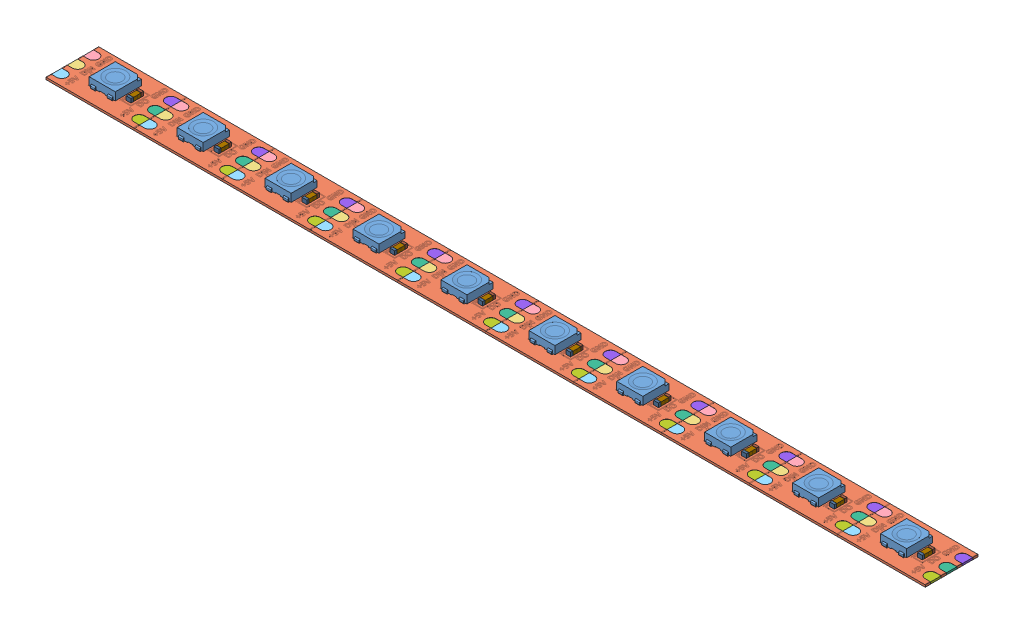
SolidWorks assembly LED_strip, configuration Défaut. Lengths in mm.
Overall size (166.7 2.05 10).
120 component instances, 11 part files, 0 mates.
Components (placement in the parent):
- WS2812B Black 60leds_m v7.step-1: WS2812B Black 60leds_m v7.step [Défaut] at (-9.957 -1.0414 11.6695) size (16.67 2.05 10)
  - WS2812_RGB_LED_updated v3.step-1: WS2812_RGB_LED_updated v3.step [Défaut] at (8.1333 0.55 5) x (1 0 0) z (0 1 0) size (4.95 5.35 1.7)
  - WS2812B Black 60leds_m.step-1: WS2812B Black 60leds_m.step [Défaut] at origin size (16.67 0.41 10)
  - WS2812B Black 60leds_m-0.step-1: WS2812B Black 60leds_m-0.step [Défaut] at origin size (2 0.36 2)
  - WS2812B Black 60leds_m-1.step-1: WS2812B Black 60leds_m-1.step [Défaut] at origin size (2 0.36 2)
  - WS2812B Black 60leds_m-2.step-1: WS2812B Black 60leds_m-2.step [Défaut] at origin size (2 0.36 2)
  - WS2812B Black 60leds_m-3.step-1: WS2812B Black 60leds_m-3.step [Défaut] at origin size (2 0.36 2)
  - WS2812B Black 60leds_m-4.step-1: WS2812B Black 60leds_m-4.step [Défaut] at origin size (2 0.36 2)
  - WS2812B Black 60leds_m-5.step-1: WS2812B Black 60leds_m-5.step [Défaut] at origin size (2 0.36 2)
  - WS2812B Black 60leds_m-6.step-1: WS2812B Black 60leds_m-6.step [Défaut] at origin size (0.9 0.7 1.5)
  - WS2812B Black 60leds_m-7.step-1: WS2812B Black 60leds_m-7.step [Défaut] at origin size (0.9 0.75 0.45)
  - WS2812B Black 60leds_m-8.step-1: WS2812B Black 60leds_m-8.step [Défaut] at origin size (0.9 0.75 0.45)
- WS2812B Black 60leds_m v7.step-2: WS2812B Black 60leds_m v7.step [Défaut] at (6.713 -1.0414 11.6695) size (16.67 2.05 10)
  - WS2812_RGB_LED_updated v3.step-1: WS2812_RGB_LED_updated v3.step [Défaut] at (8.1333 0.55 5) x (1 0 0) z (0 1 0) size (4.95 5.35 1.7)
  - WS2812B Black 60leds_m.step-1: WS2812B Black 60leds_m.step [Défaut] at origin size (16.67 0.41 10)
  - WS2812B Black 60leds_m-0.step-1: WS2812B Black 60leds_m-0.step [Défaut] at origin size (2 0.36 2)
  - WS2812B Black 60leds_m-1.step-1: WS2812B Black 60leds_m-1.step [Défaut] at origin size (2 0.36 2)
  - WS2812B Black 60leds_m-2.step-1: WS2812B Black 60leds_m-2.step [Défaut] at origin size (2 0.36 2)
  - WS2812B Black 60leds_m-3.step-1: WS2812B Black 60leds_m-3.step [Défaut] at origin size (2 0.36 2)
  - WS2812B Black 60leds_m-4.step-1: WS2812B Black 60leds_m-4.step [Défaut] at origin size (2 0.36 2)
  - WS2812B Black 60leds_m-5.step-1: WS2812B Black 60leds_m-5.step [Défaut] at origin size (2 0.36 2)
  - WS2812B Black 60leds_m-6.step-1: WS2812B Black 60leds_m-6.step [Défaut] at origin size (0.9 0.7 1.5)
  - WS2812B Black 60leds_m-7.step-1: WS2812B Black 60leds_m-7.step [Défaut] at origin size (0.9 0.75 0.45)
  - WS2812B Black 60leds_m-8.step-1: WS2812B Black 60leds_m-8.step [Défaut] at origin size (0.9 0.75 0.45)
- WS2812B Black 60leds_m v7.step-3: WS2812B Black 60leds_m v7.step [Défaut] at (23.383 -1.0414 11.6695) size (16.67 2.05 10)
  - WS2812_RGB_LED_updated v3.step-1: WS2812_RGB_LED_updated v3.step [Défaut] at (8.1333 0.55 5) x (1 0 0) z (0 1 0) size (4.95 5.35 1.7)
  - WS2812B Black 60leds_m.step-1: WS2812B Black 60leds_m.step [Défaut] at origin size (16.67 0.41 10)
  - WS2812B Black 60leds_m-0.step-1: WS2812B Black 60leds_m-0.step [Défaut] at origin size (2 0.36 2)
  - WS2812B Black 60leds_m-1.step-1: WS2812B Black 60leds_m-1.step [Défaut] at origin size (2 0.36 2)
  - WS2812B Black 60leds_m-2.step-1: WS2812B Black 60leds_m-2.step [Défaut] at origin size (2 0.36 2)
  - WS2812B Black 60leds_m-3.step-1: WS2812B Black 60leds_m-3.step [Défaut] at origin size (2 0.36 2)
  - WS2812B Black 60leds_m-4.step-1: WS2812B Black 60leds_m-4.step [Défaut] at origin size (2 0.36 2)
  - WS2812B Black 60leds_m-5.step-1: WS2812B Black 60leds_m-5.step [Défaut] at origin size (2 0.36 2)
  - WS2812B Black 60leds_m-6.step-1: WS2812B Black 60leds_m-6.step [Défaut] at origin size (0.9 0.7 1.5)
  - WS2812B Black 60leds_m-7.step-1: WS2812B Black 60leds_m-7.step [Défaut] at origin size (0.9 0.75 0.45)
  - WS2812B Black 60leds_m-8.step-1: WS2812B Black 60leds_m-8.step [Défaut] at origin size (0.9 0.75 0.45)
- WS2812B Black 60leds_m v7.step-4: WS2812B Black 60leds_m v7.step [Défaut] at (40.053 -1.0414 11.6695) size (16.67 2.05 10)
  - WS2812_RGB_LED_updated v3.step-1: WS2812_RGB_LED_updated v3.step [Défaut] at (8.1333 0.55 5) x (1 0 0) z (0 1 0) size (4.95 5.35 1.7)
  - WS2812B Black 60leds_m.step-1: WS2812B Black 60leds_m.step [Défaut] at origin size (16.67 0.41 10)
  - WS2812B Black 60leds_m-0.step-1: WS2812B Black 60leds_m-0.step [Défaut] at origin size (2 0.36 2)
  - WS2812B Black 60leds_m-1.step-1: WS2812B Black 60leds_m-1.step [Défaut] at origin size (2 0.36 2)
  - WS2812B Black 60leds_m-2.step-1: WS2812B Black 60leds_m-2.step [Défaut] at origin size (2 0.36 2)
  - WS2812B Black 60leds_m-3.step-1: WS2812B Black 60leds_m-3.step [Défaut] at origin size (2 0.36 2)
  - WS2812B Black 60leds_m-4.step-1: WS2812B Black 60leds_m-4.step [Défaut] at origin size (2 0.36 2)
  - WS2812B Black 60leds_m-5.step-1: WS2812B Black 60leds_m-5.step [Défaut] at origin size (2 0.36 2)
  - WS2812B Black 60leds_m-6.step-1: WS2812B Black 60leds_m-6.step [Défaut] at origin size (0.9 0.7 1.5)
  - WS2812B Black 60leds_m-7.step-1: WS2812B Black 60leds_m-7.step [Défaut] at origin size (0.9 0.75 0.45)
  - WS2812B Black 60leds_m-8.step-1: WS2812B Black 60leds_m-8.step [Défaut] at origin size (0.9 0.75 0.45)
- WS2812B Black 60leds_m v7.step-5: WS2812B Black 60leds_m v7.step [Défaut] at (56.723 -1.0414 11.6695) size (16.67 2.05 10)
  - WS2812_RGB_LED_updated v3.step-1: WS2812_RGB_LED_updated v3.step [Défaut] at (8.1333 0.55 5) x (1 0 0) z (0 1 0) size (4.95 5.35 1.7)
  - WS2812B Black 60leds_m.step-1: WS2812B Black 60leds_m.step [Défaut] at origin size (16.67 0.41 10)
  - WS2812B Black 60leds_m-0.step-1: WS2812B Black 60leds_m-0.step [Défaut] at origin size (2 0.36 2)
  - WS2812B Black 60leds_m-1.step-1: WS2812B Black 60leds_m-1.step [Défaut] at origin size (2 0.36 2)
  - WS2812B Black 60leds_m-2.step-1: WS2812B Black 60leds_m-2.step [Défaut] at origin size (2 0.36 2)
  - WS2812B Black 60leds_m-3.step-1: WS2812B Black 60leds_m-3.step [Défaut] at origin size (2 0.36 2)
  - WS2812B Black 60leds_m-4.step-1: WS2812B Black 60leds_m-4.step [Défaut] at origin size (2 0.36 2)
  - WS2812B Black 60leds_m-5.step-1: WS2812B Black 60leds_m-5.step [Défaut] at origin size (2 0.36 2)
  - WS2812B Black 60leds_m-6.step-1: WS2812B Black 60leds_m-6.step [Défaut] at origin size (0.9 0.7 1.5)
  - WS2812B Black 60leds_m-7.step-1: WS2812B Black 60leds_m-7.step [Défaut] at origin size (0.9 0.75 0.45)
  - WS2812B Black 60leds_m-8.step-1: WS2812B Black 60leds_m-8.step [Défaut] at origin size (0.9 0.75 0.45)
- WS2812B Black 60leds_m v7.step-6: WS2812B Black 60leds_m v7.step [Défaut] at (73.393 -1.0414 11.6695) size (16.67 2.05 10)
  - WS2812_RGB_LED_updated v3.step-1: WS2812_RGB_LED_updated v3.step [Défaut] at (8.1333 0.55 5) x (1 0 0) z (0 1 0) size (4.95 5.35 1.7)
  - WS2812B Black 60leds_m.step-1: WS2812B Black 60leds_m.step [Défaut] at origin size (16.67 0.41 10)
  - WS2812B Black 60leds_m-0.step-1: WS2812B Black 60leds_m-0.step [Défaut] at origin size (2 0.36 2)
  - WS2812B Black 60leds_m-1.step-1: WS2812B Black 60leds_m-1.step [Défaut] at origin size (2 0.36 2)
  - WS2812B Black 60leds_m-2.step-1: WS2812B Black 60leds_m-2.step [Défaut] at origin size (2 0.36 2)
  - WS2812B Black 60leds_m-3.step-1: WS2812B Black 60leds_m-3.step [Défaut] at origin size (2 0.36 2)
  - WS2812B Black 60leds_m-4.step-1: WS2812B Black 60leds_m-4.step [Défaut] at origin size (2 0.36 2)
  - WS2812B Black 60leds_m-5.step-1: WS2812B Black 60leds_m-5.step [Défaut] at origin size (2 0.36 2)
  - WS2812B Black 60leds_m-6.step-1: WS2812B Black 60leds_m-6.step [Défaut] at origin size (0.9 0.7 1.5)
  - WS2812B Black 60leds_m-7.step-1: WS2812B Black 60leds_m-7.step [Défaut] at origin size (0.9 0.75 0.45)
  - WS2812B Black 60leds_m-8.step-1: WS2812B Black 60leds_m-8.step [Défaut] at origin size (0.9 0.75 0.45)
- WS2812B Black 60leds_m v7.step-7: WS2812B Black 60leds_m v7.step [Défaut] at (90.063 -1.0414 11.6695) size (16.67 2.05 10)
  - WS2812_RGB_LED_updated v3.step-1: WS2812_RGB_LED_updated v3.step [Défaut] at (8.1333 0.55 5) x (1 0 0) z (0 1 0) size (4.95 5.35 1.7)
  - WS2812B Black 60leds_m.step-1: WS2812B Black 60leds_m.step [Défaut] at origin size (16.67 0.41 10)
  - WS2812B Black 60leds_m-0.step-1: WS2812B Black 60leds_m-0.step [Défaut] at origin size (2 0.36 2)
  - WS2812B Black 60leds_m-1.step-1: WS2812B Black 60leds_m-1.step [Défaut] at origin size (2 0.36 2)
  - WS2812B Black 60leds_m-2.step-1: WS2812B Black 60leds_m-2.step [Défaut] at origin size (2 0.36 2)
  - WS2812B Black 60leds_m-3.step-1: WS2812B Black 60leds_m-3.step [Défaut] at origin size (2 0.36 2)
  - WS2812B Black 60leds_m-4.step-1: WS2812B Black 60leds_m-4.step [Défaut] at origin size (2 0.36 2)
  - WS2812B Black 60leds_m-5.step-1: WS2812B Black 60leds_m-5.step [Défaut] at origin size (2 0.36 2)
  - WS2812B Black 60leds_m-6.step-1: WS2812B Black 60leds_m-6.step [Défaut] at origin size (0.9 0.7 1.5)
  - WS2812B Black 60leds_m-7.step-1: WS2812B Black 60leds_m-7.step [Défaut] at origin size (0.9 0.75 0.45)
  - WS2812B Black 60leds_m-8.step-1: WS2812B Black 60leds_m-8.step [Défaut] at origin size (0.9 0.75 0.45)
- WS2812B Black 60leds_m v7.step-8: WS2812B Black 60leds_m v7.step [Défaut] at (106.733 -1.0414 11.6695) size (16.67 2.05 10)
  - WS2812_RGB_LED_updated v3.step-1: WS2812_RGB_LED_updated v3.step [Défaut] at (8.1333 0.55 5) x (1 0 0) z (0 1 0) size (4.95 5.35 1.7)
  - WS2812B Black 60leds_m.step-1: WS2812B Black 60leds_m.step [Défaut] at origin size (16.67 0.41 10)
  - WS2812B Black 60leds_m-0.step-1: WS2812B Black 60leds_m-0.step [Défaut] at origin size (2 0.36 2)
  - WS2812B Black 60leds_m-1.step-1: WS2812B Black 60leds_m-1.step [Défaut] at origin size (2 0.36 2)
  - WS2812B Black 60leds_m-2.step-1: WS2812B Black 60leds_m-2.step [Défaut] at origin size (2 0.36 2)
  - WS2812B Black 60leds_m-3.step-1: WS2812B Black 60leds_m-3.step [Défaut] at origin size (2 0.36 2)
  - WS2812B Black 60leds_m-4.step-1: WS2812B Black 60leds_m-4.step [Défaut] at origin size (2 0.36 2)
  - WS2812B Black 60leds_m-5.step-1: WS2812B Black 60leds_m-5.step [Défaut] at origin size (2 0.36 2)
  - WS2812B Black 60leds_m-6.step-1: WS2812B Black 60leds_m-6.step [Défaut] at origin size (0.9 0.7 1.5)
  - WS2812B Black 60leds_m-7.step-1: WS2812B Black 60leds_m-7.step [Défaut] at origin size (0.9 0.75 0.45)
  - WS2812B Black 60leds_m-8.step-1: WS2812B Black 60leds_m-8.step [Défaut] at origin size (0.9 0.75 0.45)
- WS2812B Black 60leds_m v7.step-9: WS2812B Black 60leds_m v7.step [Défaut] at (123.403 -1.0414 11.6695) size (16.67 2.05 10)
  - WS2812_RGB_LED_updated v3.step-1: WS2812_RGB_LED_updated v3.step [Défaut] at (8.1333 0.55 5) x (1 0 0) z (0 1 0) size (4.95 5.35 1.7)
  - WS2812B Black 60leds_m.step-1: WS2812B Black 60leds_m.step [Défaut] at origin size (16.67 0.41 10)
  - WS2812B Black 60leds_m-0.step-1: WS2812B Black 60leds_m-0.step [Défaut] at origin size (2 0.36 2)
  - WS2812B Black 60leds_m-1.step-1: WS2812B Black 60leds_m-1.step [Défaut] at origin size (2 0.36 2)
  - WS2812B Black 60leds_m-2.step-1: WS2812B Black 60leds_m-2.step [Défaut] at origin size (2 0.36 2)
  - WS2812B Black 60leds_m-3.step-1: WS2812B Black 60leds_m-3.step [Défaut] at origin size (2 0.36 2)
  - WS2812B Black 60leds_m-4.step-1: WS2812B Black 60leds_m-4.step [Défaut] at origin size (2 0.36 2)
  - WS2812B Black 60leds_m-5.step-1: WS2812B Black 60leds_m-5.step [Défaut] at origin size (2 0.36 2)
  - WS2812B Black 60leds_m-6.step-1: WS2812B Black 60leds_m-6.step [Défaut] at origin size (0.9 0.7 1.5)
  - WS2812B Black 60leds_m-7.step-1: WS2812B Black 60leds_m-7.step [Défaut] at origin size (0.9 0.75 0.45)
  - WS2812B Black 60leds_m-8.step-1: WS2812B Black 60leds_m-8.step [Défaut] at origin size (0.9 0.75 0.45)
- WS2812B Black 60leds_m v7.step-10: WS2812B Black 60leds_m v7.step [Défaut] at (140.073 -1.0414 11.6695) size (16.67 2.05 10)
  - WS2812_RGB_LED_updated v3.step-1: WS2812_RGB_LED_updated v3.step [Défaut] at (8.1333 0.55 5) x (1 0 0) z (0 1 0) size (4.95 5.35 1.7)
  - WS2812B Black 60leds_m.step-1: WS2812B Black 60leds_m.step [Défaut] at origin size (16.67 0.41 10)
  - WS2812B Black 60leds_m-0.step-1: WS2812B Black 60leds_m-0.step [Défaut] at origin size (2 0.36 2)
  - WS2812B Black 60leds_m-1.step-1: WS2812B Black 60leds_m-1.step [Défaut] at origin size (2 0.36 2)
  - WS2812B Black 60leds_m-2.step-1: WS2812B Black 60leds_m-2.step [Défaut] at origin size (2 0.36 2)
  - WS2812B Black 60leds_m-3.step-1: WS2812B Black 60leds_m-3.step [Défaut] at origin size (2 0.36 2)
  - WS2812B Black 60leds_m-4.step-1: WS2812B Black 60leds_m-4.step [Défaut] at origin size (2 0.36 2)
  - WS2812B Black 60leds_m-5.step-1: WS2812B Black 60leds_m-5.step [Défaut] at origin size (2 0.36 2)
  - WS2812B Black 60leds_m-6.step-1: WS2812B Black 60leds_m-6.step [Défaut] at origin size (0.9 0.7 1.5)
  - WS2812B Black 60leds_m-7.step-1: WS2812B Black 60leds_m-7.step [Défaut] at origin size (0.9 0.75 0.45)
  - WS2812B Black 60leds_m-8.step-1: WS2812B Black 60leds_m-8.step [Défaut] at origin size (0.9 0.75 0.45)
